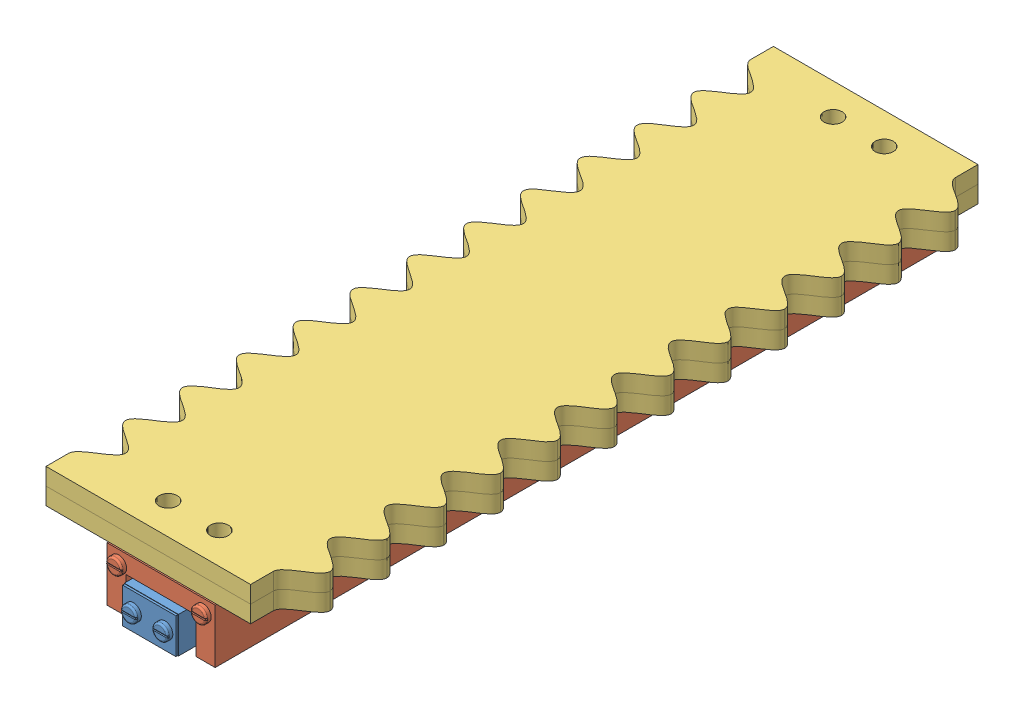
SolidWorks assembly linear_slide, configuration Default. Lengths in mm.
Overall size (37.42 16.41 131.35).
4 component instances, 3 part files, 11 mates.
Components (placement in the parent):
- EA-5BH-1: EA-5BH [Default] at origin size (9.53 6.35 130.39)
- EA-5CR-1: EA-5CR [Default] at (1.1141 0.889 -0.9629) size (19.05 9.53 130.39)
- rack-5: rack [Default] at (1.1141 10.414 63.2991) x (0 0 -1) z (1 0 0) size (128 3 37.42)
- rack-6: rack [Default] at (1.1141 13.414 63.2991) x (0 0 -1) z (1 0 0) size (128 3 37.42)
Mates (geometry in assembly coordinates):
- Concentric1: concentric aligned: cylinder of EA-5CR-1 through (-3.3859 10.414 121.7991) axis (0 1 0) radius 1.5; cylinder of ? through (-3.3859 10.414 121.7991) axis (0 1 0) radius 1.6
- Concentric2: concentric aligned: cylinder of EA-5CR-1 through (5.6141 10.414 121.7991) axis (0 1 0) radius 1.5; cylinder of ? through (5.6141 10.414 121.7991) axis (0 1 0) radius 1.6
- Concentric3: concentric aligned: cylinder of ? through (5.6141 10.414 121.7991) axis (0 1 0) radius 1.6; cylinder of ? through (5.6141 13.414 121.7991) axis (0 1 0) radius 1.6
- Concentric4: concentric aligned: cylinder of ? through (-3.3859 10.414 4.7991) axis (0 1 0) radius 1.6; cylinder of ? through (-3.3859 13.414 4.7991) axis (0 1 0) radius 1.6
- Coincident5: coincident anti-aligned: plane of ? through (1.1141 13.414 63.2991) normal (0 1 0); plane of ? through (1.1141 13.414 63.2991) normal (0 -1 0)
- Coincident6: coincident anti-aligned: plane of EA-5CR-1 through (10.6391 10.414 -0.9629) normal (0 1 0); plane of rack-5 through (1.1141 10.414 63.2991) normal (0 -1 0)
- Concentric5: concentric aligned: cylinder of EA-5CR-1 through (-3.3859 10.414 121.7991) axis (0 1 0) radius 1.5; cylinder of rack-5 through (-3.3859 10.414 121.7991) axis (0 1 0) radius 1.6
- Concentric6: concentric aligned: cylinder of EA-5CR-1 through (5.6141 10.414 121.7991) axis (0 1 0) radius 1.5; cylinder of rack-5 through (5.6141 10.414 121.7991) axis (0 1 0) radius 1.6
- Coincident7: coincident anti-aligned: plane of rack-5 through (1.1141 13.414 63.2991) normal (0 1 0); plane of rack-6 through (1.1141 13.414 63.2991) normal (0 -1 0)
- Concentric7: concentric aligned: cylinder of rack-5 through (5.6141 10.414 121.7991) axis (0 1 0) radius 1.6; cylinder of rack-6 through (5.6141 13.414 121.7991) axis (0 1 0) radius 1.6
- Concentric8: concentric aligned: cylinder of rack-5 through (-3.3859 10.414 121.7991) axis (0 1 0) radius 1.6; cylinder of rack-6 through (-3.3859 13.414 121.7991) axis (0 1 0) radius 1.6
